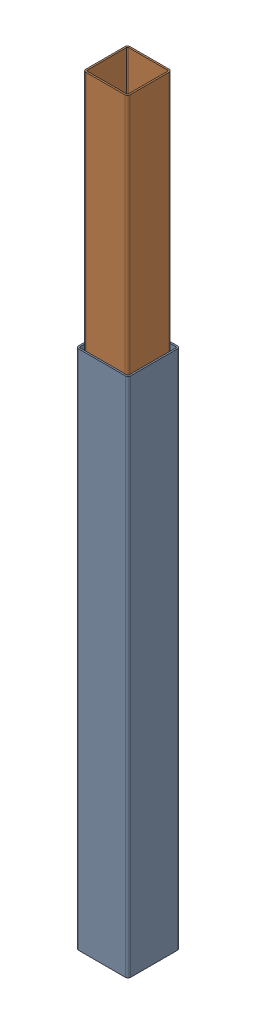
SolidWorks assembly СтойкаТеле, configuration По умолчанию. Lengths in mm.
Overall size (100 1459.84 100).
2 component instances, 2 part files, 2 mates.
Components (placement in the parent):
- Профиль100-1: Профиль100 [По умолчанию] at (407.957 414.4962 409.6523) size (100 1000 100)
- Профиль85-1: Профиль85 [По умолчанию] at (407.457 874.333 410.1523) size (85 1000 85)
Mates (geometry in assembly coordinates):
- Расстояние1: distance = 4 mm anti-aligned: plane of Профиль85-1 through (369.957 1874.333 452.6523) normal (0 0 1); plane of Профиль100-1 through (362.957 1414.4962 456.6523) normal (0 0 -1)
- Расстояние2: distance = 4 mm anti-aligned: plane of Профиль85-1 through (364.957 1874.333 372.6523) normal (-1 0 0); plane of Профиль100-1 through (360.957 1414.4962 364.6523) normal (1 0 0)
